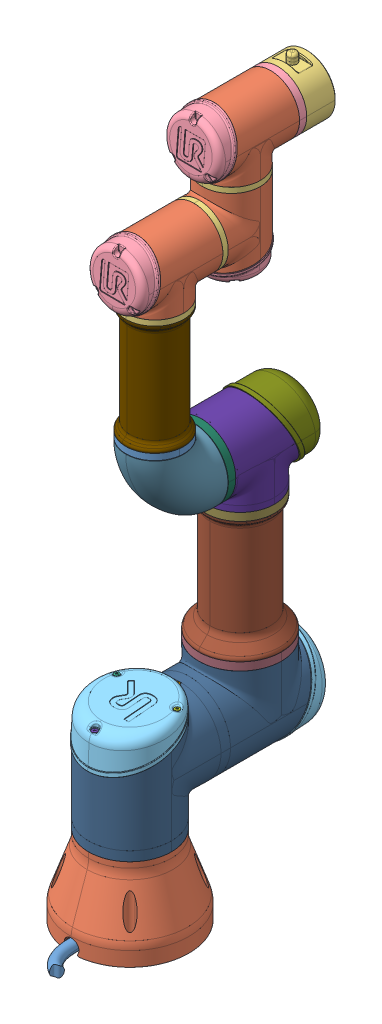
SolidWorks assembly UR3, configuration Default. Lengths in mm.
Overall size (128.1 730.97 293.78).
44 component instances, 22 part files, 0 mates.
Components (placement in the parent):
- 31220-STEP-1: 31220-STEP [Default] at origin size (128.1 86.97 164.76)
  - 31220-STEP-1: 31220-STEP [Default] at origin size (24.48 13.42 46.76)
  - 31220-STEP_1-1: 31220-STEP_1 [Default] at origin size (128.1 86.05 128)
- 31000-STEP-1: 31000-STEP [Default] at (0 691.95 -151.3) x (-1 0 0) z (0 0 1) size (63 69.6 39.8)
  - 31000-STEP-1: 31000-STEP [Default] at origin size (63 69.6 39)
  - 31000-STEP_1-1: 31000-STEP_1 [Default] at origin size (63 63 7.8)
- 31602-STEP-1: 31602-STEP [Default] at (0 84.4 0) x (-1 0 0) z (0 0 -1) size (114.19 139.03 183.8)
  - 31602-STEP_3-1: 31602-STEP_3 [Default] at origin size (114.19 64.61 104.84)
  - 31602-STEP-1: 31602-STEP [Default] at origin size (5.5 10 5.5)
  - 31602-STEP_2-1: 31602-STEP_2 [Default] at origin size (5.5 10 5.5)
  - 31602-STEP_4-1: 31602-STEP_4 [Default] at origin size (5.5 10 5.5)
  - 31602-STEP_5-1: 31602-STEP_5 [Default] at origin size (5.5 6 5.5)
  - 31602-STEP_1-1: 31602-STEP_1 [Default] at origin size (97.07 116.7 178.51)
- 31602-STEP-2: 31602-STEP [Default] at (0 151.9 -52.35) x (1 0 0) z (0 1 0) size (114.19 139.03 183.8)
  - 31602-STEP_3-1: 31602-STEP_3 [Default] at origin size (114.19 64.61 104.84)
  - 31602-STEP-1: 31602-STEP [Default] at origin size (5.5 10 5.5)
  - 31602-STEP_2-1: 31602-STEP_2 [Default] at origin size (5.5 10 5.5)
  - 31602-STEP_4-1: 31602-STEP_4 [Default] at origin size (5.5 10 5.5)
  - 31602-STEP_5-1: 31602-STEP_5 [Default] at origin size (5.5 6 5.5)
  - 31602-STEP_1-1: 31602-STEP_1 [Default] at origin size (97.07 116.7 178.51)
- 31126-STEP-1: 31126-STEP [Default] at (0 350.95 -119.85) x (0 0 -1) z (0 1 0) size (90 90 147.2)
  - 31126-STEP-1: 31126-STEP [Default] at origin size (90 90 147.2)
  - 31126-STEP_1-1: 31126-STEP_1 [Default] at origin size (75 75 8.5)
  - 31126-STEP_2-1: 31126-STEP_2 [Default] at origin size (90 90 8.65)
- 31690-STEP-1: 31690-STEP [Default] at (0 395.55 -27) x (0 0 1) z (-1 0 0) size (97.36 92.53 75.48)
  - 31690-STEP-1: 31690-STEP [Default] at origin size (97.36 92.53 75.48)
  - 31690-STEP_1-1: 31690-STEP_1 [Default] at origin size (8.1 75 75)
- 34111-STEP-1: 34111-STEP [Default] at (0 395.55 -119.85) x (0 -1 0) z (1 0 0) size (77.5 51.3 77.52)
- 31601-STEP-1: 31601-STEP [Default] at (0 395.55 -119.85) x (0 -1 0) z (1 0 0) size (83 81.72 75.22)
- 31116-STEP-1: 31116-STEP [Default] at (0 507.35 -27) x (0.990828 0 0.135131) z (0 -1 0) size (63 63 132.3)
  - 31116-STEP-1: 31116-STEP [Default] at origin size (63 63 132)
  - 31116-STEP_1-1: 31116-STEP_1 [Default] at origin size (63 63 6.8)
- 31600-STEP-1: 31600-STEP [Default] at (0 608.55 -27) x (0 -1 0) z (-1 0 0) size (76 79.05 63.01)
  - 31600-STEP-1: 31600-STEP [Default] at origin size (76 79.05 63.01)
  - 31600-STEP_1-1: 31600-STEP_1 [Default] at origin size (5.8 63 63)
- 31600-STEP-2: 31600-STEP [Default] at (0 608.55 -110.4) x (0 0 1) z (1 0 0) size (76 79.05 63.01)
  - 31600-STEP-1: 31600-STEP [Default] at origin size (76 79.05 63.01)
  - 31600-STEP_1-1: 31600-STEP_1 [Default] at origin size (5.8 63 63)
- 31600-STEP-3: 31600-STEP [Default] at (0 691.95 -110.4) x (0 -1 0) z (-1 0 0) size (76 79.05 63.01)
  - 31600-STEP-1: 31600-STEP [Default] at origin size (76 79.05 63.01)
  - 31600-STEP_1-1: 31600-STEP_1 [Default] at origin size (5.8 63 63)
- 34011-STEP-1: 34011-STEP [Default] at (0 691.95 -103.4842) x (0 1 0) z (1 0 0) size (64.55 27.63 64.61)
- 34011-STEP-2: 34011-STEP [Default] at (0 608.55 -20.0842) x (0 1 0) z (1 0 0) size (64.55 27.63 64.61)
- 34011-STEP-3: 34011-STEP [Default] at (0 601.6342 -110.4) x (0 0 -1) z (-1 0 0) size (64.55 27.63 64.61)
